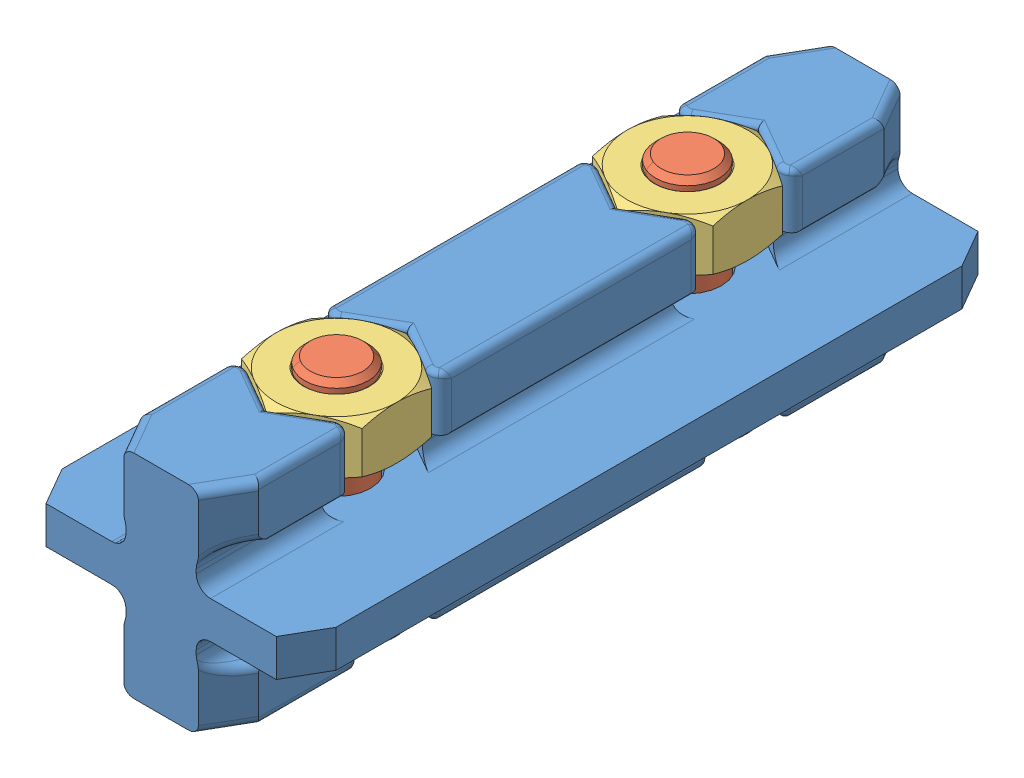
SolidWorks assembly InBetweenPiece, configuration Default. Lengths in mm.
Overall size (12.5 10.17 32.41).
49 component instances, 11 part files, 0 mates.
Components (placement in the parent):
- REV-45-1507 (1).STEP-1: REV-45-1507 (1).STEP [Default] at origin size (35.03 42.55 251.85)
  - single stage.STEP-1: single stage.STEP [Default] at origin size (35.03 35.21 251.41) (hidden)
    - REV-41-1431.STEP-1: REV-41-1431.STEP [Default] at origin size (15 15 225) (hidden)
    - REV-41-1511 V2.STEP-1: REV-41-1511 V2.STEP [Default] at (0 0 225) x (1 0 0) z (0 -1 0) size (25.27 10 16.27) (hidden)
    - REV-41-1512 V2.STEP-1: REV-41-1512 V2.STEP [Default] at (-13.3855 4 229.5) x (0 -0.999636 0.026991) z (-1 0 0) size (16.25 15.38 9.77) (hidden)
    - REV-41-1519.STEP-1: REV-41-1519.STEP [Default] at (-8.6 16.85 209) x (-1 0 0) z (0 0 1) size (7.02 29.79 32.41) (hidden)
    - REV-41-1520.STEP-1: REV-41-1520.STEP [Default] at (0 8.35 209) x (0 -1 0) z (0 0 1) size (9.73 12.5 32.41)
    - REV-41-1511 V2.STEP-2: REV-41-1511 V2.STEP [Default] x (1 0 0) z (0 1 0) size (25.27 10 16.27) (hidden)
    - REV-41-1512 V2.STEP-2: REV-41-1512 V2.STEP [Default] at (-13.3855 -4 -4.5) x (0 0.994583 -0.103946) z (-1 0 0) size (16.25 15.38 9.77) (hidden)
    - REV-41-1368.STEP-1: REV-41-1368.STEP [Default] at (-17.6355 -4 -4.5) x (0 -0.999129 0.041719) z (0 0.041719 0.999129) size (12.02 4 12.02) (hidden)
    - REV-41-1368.STEP-2: REV-41-1368.STEP [Default] at (-17.6355 4 229.5) x (0 -0.657313 0.753618) z (0 0.753618 0.657313) size (12.02 4 12.02) (hidden)
  - single stage.STEP-2: single stage.STEP [Default] at (0 16.7 225) x (1 0 0) z (0 0 -1) size (35.03 35.21 251.41)
    - REV-41-1431.STEP-1: REV-41-1431.STEP [Default] at origin size (15 15 225) (hidden)
    - REV-41-1511 V2.STEP-1: REV-41-1511 V2.STEP [Default] at (0 0 225) x (1 0 0) z (0 -1 0) size (25.27 10 16.27) (hidden)
    - REV-41-1512 V2.STEP-1: REV-41-1512 V2.STEP [Default] at (-13.3855 4 229.5) x (0 -0.999636 0.026991) z (-1 0 0) size (16.25 15.38 9.77) (hidden)
    - REV-41-1519.STEP-1: REV-41-1519.STEP [Default] at (-8.6 16.85 209) x (-1 0 0) z (0 0 1) size (7.02 29.79 32.41) (hidden)
    - REV-41-1520.STEP-1: REV-41-1520.STEP [Default] at (0 8.35 209) x (0 -1 0) z (0 0 1) size (9.73 12.5 32.41)
    - REV-41-1511 V2.STEP-2: REV-41-1511 V2.STEP [Default] x (1 0 0) z (0 1 0) size (25.27 10 16.27) (hidden)
    - REV-41-1512 V2.STEP-2: REV-41-1512 V2.STEP [Default] at (-13.3855 -4 -4.5) x (0 0.994583 -0.103946) z (-1 0 0) size (16.25 15.38 9.77) (hidden)
    - REV-41-1368.STEP-1: REV-41-1368.STEP [Default] at (-17.6355 -4 -4.5) x (0 -0.999129 0.041719) z (0 0.041719 0.999129) size (12.02 4 12.02) (hidden)
    - REV-41-1368.STEP-2: REV-41-1368.STEP [Default] at (-17.6355 4 229.5) x (0 -0.657313 0.753618) z (0 0.753618 0.657313) size (12.02 4 12.02) (hidden)
  - REV-41-1359 Simple.STEP-1: REV-41-1359 Simple.STEP [Default] at (-4.3 16.7 8) x (0 -0.430498 -0.902592) z (0 0.902592 -0.430498) size (6.36 10.01 6.36) (hidden)
  - REV-41-1361 Simple.STEP-1: REV-41-1361 Simple.STEP [Default] at (-10.5 16.7 8) x (0 -0.445235 -0.895414) z (0 0.895414 -0.445235) size (5.94 4.01 6.36) (hidden)
  - REV-41-1359 Simple.STEP-2: REV-41-1359 Simple.STEP [Default] at (-4.3 16.7 24) x (0 -0.580691 -0.814124) z (0 0.814124 -0.580691) size (6.36 10.01 6.36) (hidden)
  - REV-41-1361 Simple.STEP-2: REV-41-1361 Simple.STEP [Default] at (-10.5 16.7 24) x (0 -0.593958 -0.804496) z (0 0.804496 -0.593958) size (5.94 4.01 6.36) (hidden)
  - REV-41-1359 Simple.STEP-3: REV-41-1359 Simple.STEP [Default] at (-4.3 0 201) x (0 -0.71324 -0.70092) z (0 0.70092 -0.71324) size (6.36 10.01 6.36) (hidden)
  - REV-41-1361 Simple.STEP-3: REV-41-1361 Simple.STEP [Default] at (-10.5 0 201) x (0 -0.724633 -0.689135) z (0 0.689135 -0.724633) size (5.94 4.01 6.36) (hidden)
  - REV-41-1359 Simple.STEP-4: REV-41-1359 Simple.STEP [Default] at (-4.3 0 217) x (0 -0.824118 -0.566419) z (0 0.566419 -0.824118) size (6.36 10.01 6.36) (hidden)
  - REV-41-1361 Simple.STEP-4: REV-41-1361 Simple.STEP [Default] at (-10.5 0 217) x (0 -0.833292 -0.552834) z (0 0.552834 -0.833292) size (5.94 4.01 6.36) (hidden)
  - REV-41-1360 Simple.STEP-1: REV-41-1360 Simple.STEP [Default] at (-21.6355 20.7 229.5) x (0 0.109387 0.993999) z (0 0.993999 -0.109387) size (6.36 18.01 6.36) (hidden)
  - REV-41-1360 Simple.STEP-2: REV-41-1360 Simple.STEP [Default] at (-21.6355 4 229.5) x (0 -0.222279 0.974983) z (0 0.974983 0.222279) size (6.36 18.01 6.36) (hidden)
  - REV-41-1360 Simple.STEP-3: REV-41-1360 Simple.STEP [Default] at (-21.6355 12.7 -4.5) x (0 -0.344617 0.938743) z (0 0.938743 0.344617) size (6.36 18.01 6.36) (hidden)
  - REV-41-1360 Simple.STEP-4: REV-41-1360 Simple.STEP [Default] at (0 16.7 -9.3) x (0.896929 0.442175 0) z (0.442175 -0.896929 0) size (6.36 18.01 6.36) (hidden)
  - REV-41-1360 Simple.STEP-5: REV-41-1360 Simple.STEP [Default] at (0 0 -9.3) x (0.896929 0.442175 0) z (0.442175 -0.896929 0) size (6.36 18.01 6.36) (hidden)
  - REV-41-1360 Simple.STEP-6: REV-41-1360 Simple.STEP [Default] at (0 16.7 234.3) x (-0.153031 0.988221 0) z (-0.988221 -0.153031 0) size (6.36 18.01 6.36) (hidden)
  - REV-41-1360 Simple.STEP-7: REV-41-1360 Simple.STEP [Default] at (0 0 234.3) x (-0.194189 -0.980964 0) z (0.980964 -0.194189 0) size (6.36 18.01 6.36) (hidden)
  - REV-41-1360 Simple.STEP-8: REV-41-1360 Simple.STEP [Default] at (-21.6355 -4 -4.5) x (0 -0.489098 0.872229) z (0 0.872229 0.489098) size (6.36 18.01 6.36) (hidden)
  - REV-41-1361 Simple.STEP-5: REV-41-1361 Simple.STEP [Default] at (-9.8355 -4 -4.5) x (0 0.529919 0.848048) z (0 0.848048 -0.529919) size (5.94 4.01 6.36) (hidden)
  - REV-41-1361 Simple.STEP-6: REV-41-1361 Simple.STEP [Default] at (-9.8355 12.7 -4.5) x (0 0.529919 0.848048) z (0 0.848048 -0.529919) size (5.94 4.01 6.36) (hidden)
  - REV-41-1361 Simple.STEP-7: REV-41-1361 Simple.STEP [Default] at (-9.8355 4 229.5) x (0 -0.5 -0.866025) z (0 -0.866025 0.5) size (5.94 4.01 6.36) (hidden)
  - REV-41-1361 Simple.STEP-8: REV-41-1361 Simple.STEP [Default] at (-9.8355 20.7 229.5) x (0 -0.5 -0.866025) z (0 -0.866025 0.5) size (5.94 4.01 6.36) (hidden)
  - M3 x 8mm low profile socket.STEP-1: M3 x 8mm low profile socket.STEP [Default] at (0 5.65 24) x (-0.837169 0 -0.546944) z (-0.546944 0 0.837169) size (5.4 9.8 5.4)
  - hex nut style 1_am_B18.2.4.1M - Hex nut, Style 1,  M3 x 0.5 --D-N.STEP-1: hex nut style 1_am_B18.2.4.1M - Hex nut, Style 1,  M3 x 0.5 --D-N.STEP [Default] at (0 13.2 24) x (0.5 0 -0.866025) z (0 1 0) size (6.36 6.36 2.41)
  - M3 x 8mm low profile socket.STEP-2: M3 x 8mm low profile socket.STEP [Default] at (0 5.65 8) x (-0.925243 0 -0.379375) z (-0.379375 0 0.925243) size (5.4 9.8 5.4)
  - hex nut style 1_am_B18.2.4.1M - Hex nut, Style 1,  M3 x 0.5 --D-N.STEP-2: hex nut style 1_am_B18.2.4.1M - Hex nut, Style 1,  M3 x 0.5 --D-N.STEP [Default] at (0 13.2 8) x (1 0 0) z (0 1 0) size (6.36 6.36 2.41)
  - hex nut style 1_am_B18.2.4.1M - Hex nut, Style 1,  M3 x 0.5 --D-N.STEP-3: hex nut style 1_am_B18.2.4.1M - Hex nut, Style 1,  M3 x 0.5 --D-N.STEP [Default] at (0 3.5 217) x (-0.5 0 0.866025) z (0 -1 0) size (6.36 6.36 2.41) (hidden)
  - M3 x 8mm low profile socket.STEP-3: M3 x 8mm low profile socket.STEP [Default] at (0 11.05 217) x (-0.546944 0 -0.837169) z (0.837169 0 -0.546944) size (5.4 9.8 5.4) (hidden)
  - hex nut style 1_am_B18.2.4.1M - Hex nut, Style 1,  M3 x 0.5 --D-N.STEP-4: hex nut style 1_am_B18.2.4.1M - Hex nut, Style 1,  M3 x 0.5 --D-N.STEP [Default] at (0 3.5 201) x (-0.5 0 0.866025) z (0 -1 0) size (6.36 6.36 2.41) (hidden)
  - M3 x 8mm low profile socket.STEP-4: M3 x 8mm low profile socket.STEP [Default] at (0 11.05 201) x (-0.546944 0 -0.837169) z (0.837169 0 -0.546944) size (5.4 9.8 5.4) (hidden)
